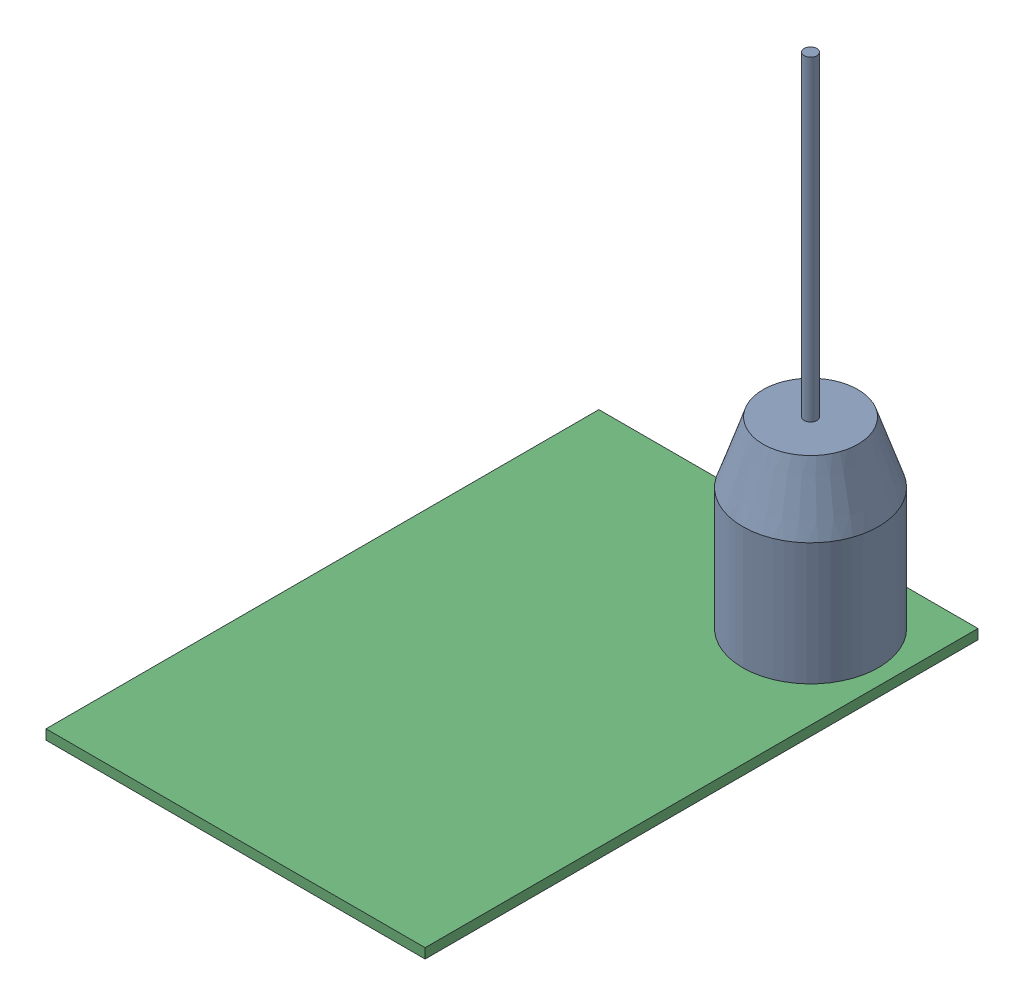
SolidWorks assembly Spade mount assembly, configuration large plate. Lengths in mm.
Overall size (120 169.06 175).
3 component instances, 3 part files, 4 mates.
Components (placement in the parent):
- Chuck with drill bit-1: Chuck with drill bit [Default] at (33.6393 29.5564 11.7711) x (0.997696 0 -0.067843) z (0.067843 0 0.997696) size (43 158 43)
- 93190A384_Super-Corrosion-Resistant 316 Stainless Steel Hex Head Screw 1.5 in long 1-2 20UNF-1: 93190A384_Super-Corrosion-Resistant 316 Stainless Steel Hex Head Screw 1.5 in long 1-2 20UNF [93190A384] at (33.6393 41.5127 11.7711) x (1 0 0) z (0 -1 0) size (19.05 22 46.49)
- large base plate-1: large base plate [Default] at (-59.8607 29.5564 160.2711) x (0 0 -1) z (-1 0 0) size (175 3.12 120)
Mates (geometry in assembly coordinates):
- Concentric4: concentric aligned: cylinder of Chuck with drill bit-1 through (33.6393 29.5564 11.7711) axis (0 -1 0) radius 5.7544; cylinder of large base plate-1 through (33.6393 23.3064 11.7711) axis (0 -1 0) radius 5.7544
- Concentric5: concentric anti-aligned: cylinder of Chuck with drill bit-1 through (33.6393 29.5564 11.7711) axis (0 -1 0) radius 21.5; cylinder of 93190A384_Super-Corrosion-Resistant 316 Stainless Steel Hex Head Screw 1.5 in long 1-2 20UNF-1 through (33.6393 23.108 11.7711) axis (0 1 0) radius 9.0488
- Coincident7: coincident anti-aligned: plane of 93190A384_Super-Corrosion-Resistant 316 Stainless Steel Hex Head Screw 1.5 in long 1-2 20UNF-1 through (24.5906 23.3064 11.7711) normal (0 1 0); plane of large base plate-1 through (-59.8607 23.3064 160.2711) normal (0 -1 0)
- Coincident8: coincident anti-aligned: plane of Chuck with drill bit-1 through (55.0898 29.5564 10.3125) normal (0 -1 0); plane of large base plate-1 through (-59.8607 29.5564 160.2711) normal (0 1 0)
